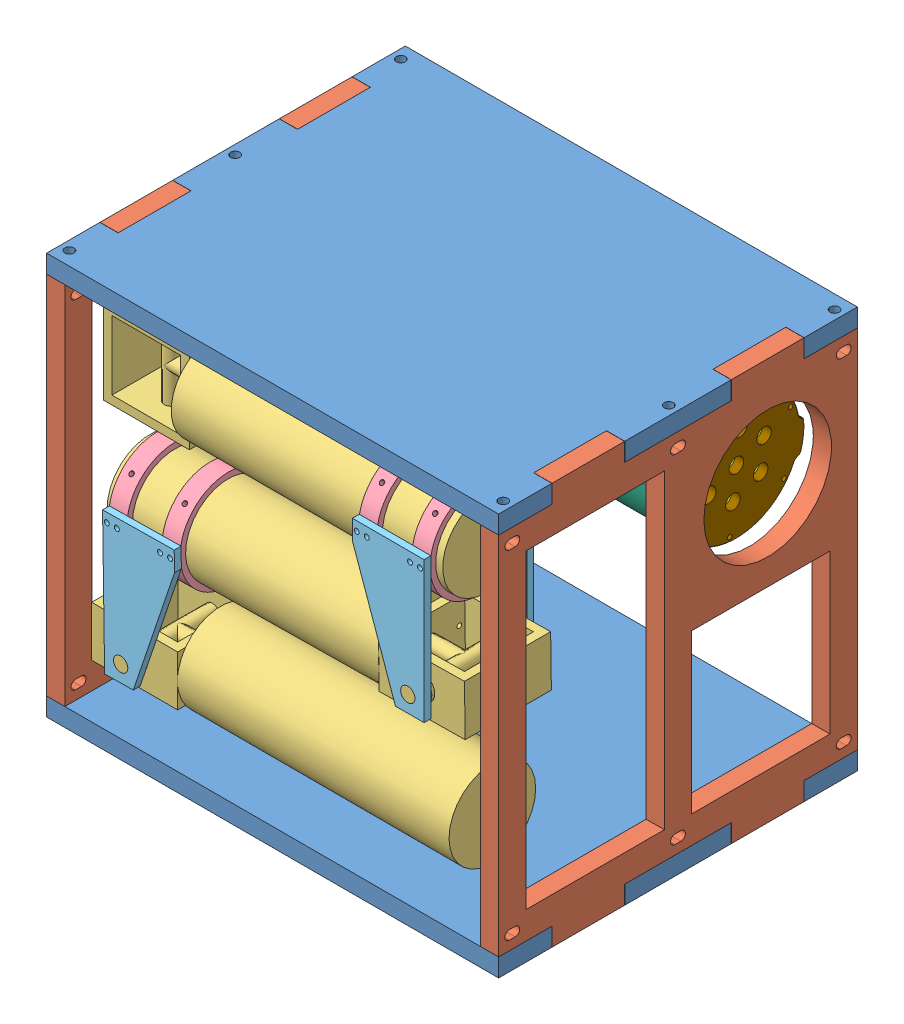
SolidWorks assembly EnsamblajeCompletoRobot, configuration Predeterminado. Lengths in mm.
Overall size (315 280 268.36).
22 component instances, 9 part files, 12 mates.
Components (placement in the parent):
- TP_Base-1: TP_Base [Predeterminado] at origin size (315 12.7 250)
- Side_Base-1: Side_Base [Predeterminado] at (-157.5 -127.3 0) x (0 0 -1) z (1 0 0) size (250 280 12.7)
- Side_Base-2: Side_Base [Predeterminado] at (144.8 -127.3 0) x (0 0 -1) z (1 0 0) size (250 280 12.7)
- EnsamblajeBrazoV2_2-1: EnsamblajeBrazoV2_2 [Predeterminado] at (-100.5 -38.75 95) x (0 1 0) z (0.999999 0 0.001167) size (242.51 97.75 263.59)
  - EslabonSimplificado-1: EslabonSimplificado [Predeterminado] at origin size (79.5 60.33 249.5)
  - SujeccionMotorV2-1: SujeccionMotorV2 [Predeterminado] at (0 0 208.15) x (0.707107 -0.707107 0) z (0 0 1) size (68 68 12.7)
  - SujeccionMotorV2-2: SujeccionMotorV2 [Predeterminado] at (0 0 171) x (0.707107 -0.707107 0) z (0 0 1) size (68 68 12.7)
  - Soporte-3: Soporte [Predeterminado] at (6.35 33.4018 214.5) x (0 0 1) z (0 1 0) size (50 98.35 4.76)
  - Soporte-4: Soporte [Predeterminado] at (6.35 -38.1643 214.5) x (0 0 1) z (0 1 0) size (50 98.35 4.76)
  - EslabonSimplificado-2: EslabonSimplificado [Predeterminado] at (-80.65 -1.5857 203.15) x (0 1 0) z (-0.014607 0 -0.999893) size (79.5 60.33 249.5)
  - SujeccionMotorV2-3: SujeccionMotorV2 [Predeterminado] at (-83.6904 -1.5857 -4.9778) x (-0.707031 -0.707107 0.010329) z (-0.014607 0 -0.999893) size (68 68 12.7)
  - SujeccionMotorV2-4: SujeccionMotorV2 [Predeterminado] at (-83.1478 -1.5857 32.1682) x (-0.707031 -0.707107 0.010329) z (-0.014607 0 -0.999893) size (68 68 12.7)
  - Soporte-7: Soporte [Predeterminado] at (-77.4338 36.5785 -11.4199) x (-0.014607 0 -0.999893) z (0 -1 0) size (50 98.35 4.76)
  - Soporte-8: Soporte [Predeterminado] at (-77.4338 -34.9875 -11.4199) x (-0.014607 0 -0.999893) z (0 -1 0) size (50 98.35 4.76)
  - EslabonSimplificado-4: EslabonSimplificado [Predeterminado] at (-164.2588 -3.1715 1.1997) x (0 1 0) z (0 0 1) size (79.5 60.33 249.5)
- EnsambleTubo-1: EnsambleTubo [Predeterminado] at (123.7041 -62.5 -62.5) x (1 0 0) z (0 0.011715 0.999931) size (292.35 100.44 103.58)
  - WTE3-P-LOCKING-TUBE-240-R2-1: WTE3-P-LOCKING-TUBE-240-R2 [Predeterminado] at origin size (240.01 88.9 88.9)
  - WTE3-M-LOCKING-FLANGE-SEAL-R1-RP-1: WTE3-M-LOCKING-FLANGE-SEAL-R1-RP [Predeterminado] at (-21 0 0) x (0 0 -1) z (1 0 0) size (88.9 95.83 27.56)
  - WTE3-M-LOCKING-FLANGE-SEAL-R1-RP-2: WTE3-M-LOCKING-FLANGE-SEAL-R1-RP [Predeterminado] at (-219 0 0) x (0 0 1) z (-1 0 0) size (88.9 95.83 27.56)
  - WTE3-P-DOME-R1-1: WTE3-P-DOME-R1 [Default] at (-246 0 0) x (0 0.996902 0.078658) z (0 -0.078658 0.996902) size (79.25 34.35 79.25)
  - WTE3-M-END-CAP-7-HOLE-R1-1: WTE3-M-END-CAP-7-HOLE-R1 [Default] at (6 0 0) x (0 -0.102065 -0.994778) z (1 0 0) size (95 88.9 6)
- TP_Base-2: TP_Base [Predeterminado] at (0 -267.3 0) size (315 12.7 250)
Mates (geometry in assembly coordinates):
- Coincidente1: coincident anti-aligned: plane of TP_Base-1 through (-144.8 0 87.9) normal (-1 0 0); plane of Side_Base-1 through (-144.8 -127.3 0) normal (1 0 0)
- Coincidente2: coincident anti-aligned: plane of TP_Base-1 through (0 0 0) normal (0 -1 0); plane of Side_Base-1 through (-157.5 0 125) normal (0 1 0)
- Coincidente3: coincident aligned: plane of TP_Base-1 through (-157.5 12.7 125) normal (0 0 1); plane of Side_Base-1 through (-144.8 -267.3 125) normal (0 0 1)
- Coincidente4: coincident anti-aligned: plane of TP_Base-1 through (0 0 0) normal (0 -1 0); plane of Side_Base-2 through (144.8 0 125) normal (0 1 0)
- Coincidente5: coincident anti-aligned: plane of TP_Base-1 through (144.8 0 87.9) normal (1 0 0); plane of Side_Base-2 through (144.8 -127.3 0) normal (-1 0 0)
- Coincidente6: coincident aligned: plane of TP_Base-1 through (-157.5 12.7 125) normal (0 0 1); plane of Side_Base-2 through (157.5 -267.3 125) normal (0 0 1)
- Coincidente7: coincident anti-aligned: plane of Side_Base-1 through (-157.5 -254.6 125) normal (0 -1 0); plane of TP_Base-2 through (0 -254.6 0) normal (0 1 0)
- Coincidente8: coincident aligned: plane of Side_Base-1 through (-144.8 -267.3 125) normal (0 0 1); plane of TP_Base-2 through (-157.5 -254.6 125) normal (0 0 1)
- Coincidente9: coincident aligned: plane of Side_Base-1 through (-157.5 -127.3 0) normal (-1 0 0); plane of TP_Base-2 through (-157.5 -254.6 125) normal (-1 0 0)
- Concéntrica1: concentric aligned: circle of Side_Base-2; circle of EnsambleTubo-1/WTE3-M-END-CAP-7-HOLE-R1-1
- Concéntrica2: concentric anti-aligned: circle of TP_Base-1; circle of EnsamblajeBrazoV2_2-1/EslabonSimplificado-1
- Coincidente10: coincident anti-aligned: plane of TP_Base-1 through (-100.5 1 95) normal (0 -1 0); plane of EnsamblajeBrazoV2_2-1/EslabonSimplificado-1 through (-100.5 1 95) normal (0 1 0)
